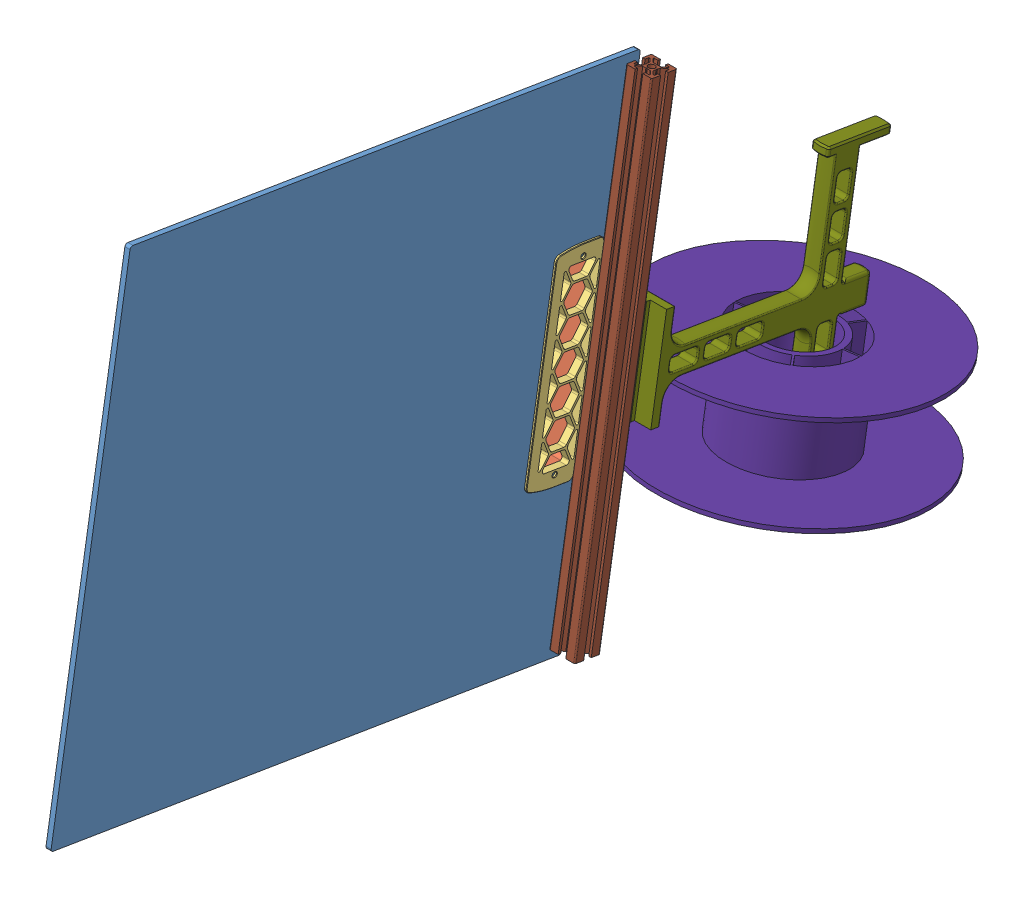
SolidWorks assembly ExhaustHousingV2, configuration Default. Lengths in mm.
Overall size (231.84 443.28 670.99).
33 component instances, 20 part files, 76 mates.
Components (placement in the parent):
- RearPanelV2-1: RearPanelV2 [Default] at (-5.1264 381.0848 346.6202) x (-1 0 0) z (0 -0.162169 -0.986763) size (4 383 403)
- FilterHousing-1: FilterHousing [Default] at (-45.6333 239.2101 122.0533) x (0 -0.986763 0.162169) z (1 0 0) size (147.2 124.67 63)
- Exhaust Grill-1: Exhaust Grill [Default] at (-84.6683 239.4745 118.2405) x (1 0 0) z (0 -0.162169 -0.986763) size (5.6 154.8 37.6)
- RoombaFilter-1: RoombaFilter [Default] at (11.8167 226.6956 67.4621) x (0 -0.986763 0.162169) z (0 -0.162169 -0.986763) size (111 58.5 10.6)
- 6020 Fan-1: 6020 Fan [Default] at (-19.2567 180.7716 130.8499) x (1 0 0) z (0 -0.162169 -0.986763) size (60 60 20.73)
  - 6020 Impeller-1: 6020 Impeller [Default] at origin size (57.63 56.86 10.88)
  - 6020 Housing-1: 6020 Housing [Default] at origin size (60 60 20.73)
- 60mm_exhaust_fan_grill-1: 60mm_exhaust_fan_grill [Default] at (-103.0418 277.1852 53.6413) x (0 -0.162169 -0.986763) z (-1 0 0) size (3.2 60 60)
- M3x30 SHCS (23)-1: M3x30 SHCS (23) [Default] at (11.2417 204.1424 113.6814) x (0.591782 0.795427 -0.130724) z (0 -0.162169 -0.986763) size (5.5 5.5 33.14)
- M3x30 SHCS (23)-2: M3x30 SHCS (23) [Default] at (11.2417 154.4342 121.8506) x (1 0 0) z (0 -0.162169 -0.986763) size (5.5 5.5 33.14)
- M3x30 SHCS (23)-3: M3x30 SHCS (23) [Default] at (-39.1333 154.4342 121.8506) x (1 0 0) z (0 -0.162169 -0.986763) size (5.5 5.5 33.14)
- M3x30 SHCS (23)-4: M3x30 SHCS (23) [Default] at (-39.1333 204.1424 113.6814) x (1 0 0) z (0 -0.162169 -0.986763) size (5.5 5.5 33.14)
- SF2-1: SF2 [Default] at (-36.5033 186.0161 -0.4675) x (0 -0.986763 0.162169) z (-0.707107 0.114671 0.697747) size (53 27 31)
- M3x8 SHCS (91)-3: M3x8 SHCS (91) [Default] at (-49.2312 178.623 40.8767) x (0.696904 -0.054007 0.715128) z (-0.707107 0.114671 0.697747) size (5.5 5.5 11.14)
- M3x8 SHCS (91)-2: M3x8 SHCS (91) [Default] at (-58.0701 152.5205 36.2091) x (-0.176014 0.927159 -0.330749) z (-0.707107 0.114671 0.697747) size (5.5 5.5 11.14)
- M3x8 SHCS (91)-1: M3x8 SHCS (91) [Default] at (-49.2312 153.9539 44.9309) x (0.040643 0.991723 -0.121796) z (-0.707107 0.114671 0.697747) size (5.5 5.5 11.14)
- HFSB5-2020-370-TPW-1: HFSB5-2020-370-TPW [Default] at (210.7912 17.5776 81.3371) x (-1 0 0) z (0 -0.986763 0.162169) size (20 20 370)
  - HFSB5-2020-370-TPW (1)-1: HFSB5-2020-370-TPW (1) [Default] at (179.4245 40.4288 32.2963) size (20 20 370)
  - 2020 Drop-in T-nut, M5-1-1: 2020 Drop-in T-nut, M5-1 [Default] at (188.0245 39.8788 -223.8496) x (0 1 0) z (0 0 -1) size (7.7 4.3 13)
  - 2020 Drop-in T-nut, M5-2-1: 2020 Drop-in T-nut, M5-2 [Default] at (188.0245 39.8788 -81.775) x (0 -1 0) z (0 0 1) size (7.7 4.3 13)
- ExhaustSpacer-1: ExhaustSpacer [Default] at (-84.6683 239.5069 118.4376) x (1 0 0) z (0 -0.162169 -0.986763) size (4 146.4 51.6)
- M5x10 BHCS-1: M5x10 BHCS [Default] at (14.6167 99.6972 27.4274) x (0 -0.535626 -0.844456) z (-1 0 0) size (9.57 9.61 13.38)
- M5x10 BHCS-2: M5x10 BHCS [Default] at (14.6167 224.424 6.9292) x (0 -0.013666 -0.999907) z (-1 0 0) size (9.57 9.61 13.38)
- SpoolHolderfor2V2-1: SpoolHolderfor2V2 [Default] at (153.0824 49.3334 -39.749) x (0 -0.162169 -0.986763) z (1 0 0) size (176.82 207.23 38.86)
- FilamentSpool200x72mm-1: FilamentSpool200x72mm [Default] at (47.0709 125.7193 -111.542) x (0.984651 -0.028305 -0.172227) z (0 -0.986763 0.162169) size (200 200 73.24)
- CharcoalBoxV2-1: CharcoalBoxV2 [Default] at (-45.6333 119.2164 123.3821) x (0 -0.162169 -0.986763) z (1 0 0) size (49.75 119.5 71)
- M3 Threaded Insert-1: M3 Threaded Insert [Default] at (-39.1333 155.0748 125.7483) x (1 0 0) z (0 0.162169 0.986763) size (5 5 3.85)
- M3 Threaded Insert-2: M3 Threaded Insert [Default] at (-39.1333 204.413 117.6399) x (1 0 0) z (0 0.162169 0.986763) size (5 5 3.85)
- M3 Threaded Insert-3: M3 Threaded Insert [Default] at (10.8667 155.0748 125.7483) x (1 0 0) z (0 0.162169 0.986763) size (5 5 3.85)
- M3 Threaded Insert-4: M3 Threaded Insert [Default] at (10.8667 204.413 117.6399) x (1 0 0) z (0 0.162169 0.986763) size (5 5 3.85)
- M3 Threaded Insert-5: M3 Threaded Insert [Default] at (13.5167 234.4299 31.4309) x (0 0 -1) z (1 0 0) size (5 5 3.85)
- M3 Threaded Insert-6: M3 Threaded Insert [Default] at (13.5167 98.0592 53.8427) x (0 -0.087212 -0.99619) z (1 0 0) size (5 5 3.85)
- SFSReplacement-1: SFSReplacement [Default] at (-18.8257 136.091 25.6522) x (0 0.986763 -0.162169) z (-0.707107 0.114671 0.697747) size (53.9 25 25)
Mates (geometry in assembly coordinates):
- Distance5: distance = 4 mm: line of 6020 Fan (1)-1/RoombaFilter-1 through (-41.1837 -52 36) axis (1 0 0); plane of FilterHousing-1 through (17.3667 111.7222 84.1699) normal (0 -0.156807 -0.987629)
- Distance6: distance = 38.5 mm anti-aligned: plane of FilterHousing-1 through (-45.6333 239.2101 122.0533) normal (0 -0.986763 0.162169); plane of 6020 Fan (1)-1/RoombaFilter-1 through (-41.1837 -19 34) normal (0 -1 0)
- Distance7: distance = 4 mm: line of 6020 Fan (1)-1/RoombaFilter-2 through (-41.1837 -52 36) axis (1 0 0); plane of FilterHousing-1 through (17.3667 111.7222 84.1699) normal (0 -0.156807 -0.987629)
- Distance8: distance = 38.5 mm anti-aligned: plane of FilterHousing-1 through (-45.6333 239.2101 122.0533) normal (0 -0.986763 0.162169); plane of 6020 Fan (1)-1/RoombaFilter-2 through (-41.1837 -19 34) normal (0 -1 0)
- Concentric19: concentric aligned: cylinder of M3x30 SHCS (23)-3 through (-39.1333 159.2993 151.4535) axis (0 -0.162169 -0.986763) radius 1.5; cylinder of 60mm_exhaust_fan_grill-1 through (-39.1333 159.4615 152.4403) axis (0 -0.162169 -0.986763) radius 1.75
- Concentric20: concentric aligned: cylinder of M3x30 SHCS (23)-4 through (-39.1333 209.0075 143.2843) axis (0 -0.162169 -0.986763) radius 1.5; cylinder of 60mm_exhaust_fan_grill-1 through (-39.1333 209.1697 144.271) axis (0 -0.162169 -0.986763) radius 1.75
- Concentric21: concentric aligned: cylinder of M3x30 SHCS (23)-2 through (11.2417 159.2993 151.4535) axis (0 -0.162169 -0.986763) radius 1.5; cylinder of 60mm_exhaust_fan_grill-1 through (11.2417 159.4615 152.4403) axis (0 -0.162169 -0.986763) radius 1.75
- Concentric22: concentric aligned: cylinder of M3x30 SHCS (23)-1 through (11.2417 209.0075 143.2843) axis (0 -0.162169 -0.986763) radius 1.5; cylinder of 60mm_exhaust_fan_grill-1 through (11.2417 209.1697 144.271) axis (0 -0.162169 -0.986763) radius 1.75
- Coincident45: coincident anti-aligned: plane of M3x30 SHCS (23)-1 through (11.2417 209.0075 143.2843) normal (0 -0.162169 -0.986763); plane of 60mm_exhaust_fan_grill-1 through (11.2417 209.0075 143.2843) normal (0 0.162169 0.986763)
- Coincident46: coincident anti-aligned: plane of M3x30 SHCS (23)-4 through (-39.1333 209.0075 143.2843) normal (0 -0.162169 -0.986763); plane of 60mm_exhaust_fan_grill-1 through (-39.1333 209.0075 143.2843) normal (0 0.162169 0.986763)
- Coincident47: coincident anti-aligned: plane of M3x30 SHCS (23)-3 through (-39.1333 159.2993 151.4535) normal (0 -0.162169 -0.986763); plane of 60mm_exhaust_fan_grill-1 through (-39.1333 159.2993 151.4535) normal (0 0.162169 0.986763)
- Coincident48: coincident anti-aligned: plane of M3x30 SHCS (23)-2 through (11.2417 159.2993 151.4535) normal (0 -0.162169 -0.986763); plane of 60mm_exhaust_fan_grill-1 through (11.2417 159.2993 151.4535) normal (0 0.162169 0.986763)
- Coincident49: coincident anti-aligned: plane of 6020 Fan (1)-1/6020 Housing (1)-1 through (-39.6333 158.8192 149.3029) normal (0 0.162169 0.986763); plane of 60mm_exhaust_fan_grill-1 through (-13.9458 183.7966 145.198) normal (0 -0.162169 -0.986763)
- Concentric23: concentric aligned: cylinder of 6020 Fan (1)-1/6020 Housing (1)-1 through (-39.1333 204.5965 116.4443) axis (0 -0.162169 -0.986763) radius 2.25; cylinder of M3x30 SHCS (23)-4 through (-39.1333 209.0075 143.2843) axis (0 -0.162169 -0.986763) radius 1.5
- Parallel8: parallel aligned: plane of FilterHousing-1 through (-45.6333 239.2101 122.0533) normal (-1 0 0); plane of 6020 Fan (1)-1/6020 Housing (1)-1 through (-44.1333 154.765 124.6338) normal (-1 0 0)
- Parallel13: parallel aligned: plane of FilterHousing-1 through (-45.6333 239.2101 122.0533) normal (-1 0 0); plane of 6020 Fan (1)-1/6020 Housing (1)-1 through (-44.1333 154.765 124.6338) normal (-1 0 0)
- Concentric31: concentric aligned: cylinder of ExhaustSpacer-1 through (17.3667 99.6972 27.4274) axis (1 0 0) radius 2.75; cylinder of M5x10 BHCS-1 through (27.3667 99.6972 27.4274) axis (1 0 0) radius 2.5
- Concentric32: concentric aligned: cylinder of ExhaustSpacer-1 through (17.3667 224.424 6.9292) axis (1 0 0) radius 2.75; cylinder of M5x10 BHCS-2 through (27.3667 224.424 6.9292) axis (1 0 0) radius 2.5
- Coincident77: coincident anti-aligned: plane of ExhaustSpacer-1 through (17.3667 239.5069 118.4376) normal (-1 0 0); plane of M5x10 BHCS-2 through (17.3667 229.1736 6.8643) normal (1 0 0)
- Coincident78: coincident anti-aligned: plane of ExhaustSpacer-1 through (17.3667 239.5069 118.4376) normal (-1 0 0); plane of M5x10 BHCS-1 through (17.3667 103.7083 24.8832) normal (1 0 0)
- Coincident83: coincident anti-aligned: plane of HFSB5-2020-370-TPW-1/HFSB5-2020-370-TPW (1)-1 through (34.3667 342.6332 -23.1893) normal (0 -0.162169 -0.986763); plane of SpoolHolderfor2V2-1 through (153.0824 59.6968 23.3097) normal (0 0.162169 0.986763)
- Coincident84: coincident anti-aligned: plane of HFSB5-2020-370-TPW-1/HFSB5-2020-370-TPW (1)-1 through (34.3667 342.9575 -21.2158) normal (-1 0 0); plane of SpoolHolderfor2V2-1 through (34.3667 198.552 6.5701) normal (1 0 0)
- Distance21: distance = 3 mm anti-aligned: plane of FilamentSpool200x72mm-1 through (47.0709 125.7193 -111.542) normal (0 0.986763 -0.162169); plane of SpoolHolderfor2V2-1 through (61.3108 127.2962 -120.4458) normal (0 -0.986763 0.162169)
- Concentric33: concentric aligned: cylinder of M3x30 SHCS (23)-3 through (-39.1333 159.2993 151.4535) axis (0 -0.162169 -0.986763) radius 1.5; cylinder of 6020 Fan (1)-1/60mm_exhaust_fan_grill-1 through (-39.6333 154.8032 133.1909) axis (0 -0.162169 -0.986763) radius 1.75
- Concentric34: concentric aligned: cylinder of M3x30 SHCS (23)-4 through (-39.1333 209.0075 143.2843) axis (0 -0.162169 -0.986763) radius 1.5; cylinder of 6020 Fan (1)-1/60mm_exhaust_fan_grill-1 through (-39.6333 204.5114 125.0216) axis (0 -0.162169 -0.986763) radius 1.75
- Concentric35: concentric aligned: cylinder of M3x30 SHCS (23)-2 through (11.2417 159.2993 151.4535) axis (0 -0.162169 -0.986763) radius 1.5; cylinder of 6020 Fan (1)-1/60mm_exhaust_fan_grill-1 through (10.7417 154.8032 133.1909) axis (0 -0.162169 -0.986763) radius 1.75
- Concentric36: concentric aligned: cylinder of M3x30 SHCS (23)-1 through (11.2417 209.0075 143.2843) axis (0 -0.162169 -0.986763) radius 1.5; cylinder of 6020 Fan (1)-1/60mm_exhaust_fan_grill-1 through (10.7417 204.5114 125.0216) axis (0 -0.162169 -0.986763) radius 1.75
- Coincident95: coincident anti-aligned: plane of M3x30 SHCS (23)-1 through (11.2417 209.0075 143.2843) normal (0 -0.162169 -0.986763); plane of 6020 Fan (1)-1/60mm_exhaust_fan_grill-1 through (10.7417 204.3492 124.0349) normal (0 0.162169 0.986763)
- Coincident96: coincident anti-aligned: plane of M3x30 SHCS (23)-4 through (-39.1333 209.0075 143.2843) normal (0 -0.162169 -0.986763); plane of 6020 Fan (1)-1/60mm_exhaust_fan_grill-1 through (-39.6333 204.3492 124.0349) normal (0 0.162169 0.986763)
- Coincident97: coincident anti-aligned: plane of M3x30 SHCS (23)-3 through (-39.1333 159.2993 151.4535) normal (0 -0.162169 -0.986763); plane of 6020 Fan (1)-1/60mm_exhaust_fan_grill-1 through (-39.6333 154.641 132.2041) normal (0 0.162169 0.986763)
- Coincident98: coincident anti-aligned: plane of M3x30 SHCS (23)-2 through (11.2417 159.2993 151.4535) normal (0 -0.162169 -0.986763); plane of 6020 Fan (1)-1/60mm_exhaust_fan_grill-1 through (10.7417 154.641 132.2041) normal (0 0.162169 0.986763)
- Coincident103: coincident anti-aligned: plane of RoombaFilter-1 through (11.8167 226.6956 67.4621) normal (0 0.162169 0.986763); plane of CarcoalBoxV2-1 through (-45.6333 113.0945 86.1318) normal (0 -0.162169 -0.986763)
- Coincident104: coincident aligned: line of RoombaFilter-1 through (10.8173 117.1649 85.4629) axis (-1 0 0); line of CarcoalBoxV2-1 through (11.9167 117.1649 85.4629) axis (-1 0 0)
- Coincident105: coincident aligned: line of RoombaFilter-1 through (-43.1833 118.1511 85.3008) axis (0 0.986763 -0.162169); line of CarcoalBoxV2-1 through (-43.1833 117.1649 85.4629) axis (0 0.986763 -0.162169)
- Distance26: distance = 0.1 mm anti-aligned: plane of FilterHousing-1 through (-42.7333 119.6043 126.3586) normal (0 0.986763 -0.162169); plane of CarcoalBoxV2-1 through (14.3667 119.2164 123.3821) normal (0 -0.986763 0.162169)
- Coincident107: coincident anti-aligned: plane of FilterHousing-1 through (-36.5033 186.5095 -0.5486) normal (-0.707107 0.114671 0.697747); plane of SF2-1 through (-36.5033 186.0161 -0.4675) normal (0.707107 -0.114671 -0.697747)
- Coincident108: coincident aligned: plane of FilterHousing-1 through (-105.831 229.4478 62.6524) normal (-0.707107 -0.114671 -0.697747); plane of SF2-1 through (-54.181 188.8828 16.9762) normal (-0.707107 -0.114671 -0.697747)
- Distance27: distance = 47 mm aligned: plane of SF2-1 through (-54.181 188.8828 16.9762) normal (0 0.986763 -0.162169); plane of FilterHousing-1 through (-45.6333 236.0634 14.2384) normal (0 0.986763 -0.162169)
- Concentric37: concentric anti-aligned: cylinder of FilterHousing-1 through (-39.1333 153.7531 117.7062) axis (0 0.162169 0.986763) radius 2.1; cylinder of M3 Threaded Insert-1 through (-39.1333 155.0748 125.7483) axis (0 -0.162169 -0.986763) radius 1.45
- Concentric38: concentric anti-aligned: cylinder of FilterHousing-1 through (10.8667 153.7531 117.7062) axis (0 0.162169 0.986763) radius 2.1; cylinder of M3 Threaded Insert-3 through (10.8667 155.0748 125.7483) axis (0 -0.162169 -0.986763) radius 1.45
- Concentric39: concentric anti-aligned: cylinder of FilterHousing-1 through (-39.1333 203.0913 109.5978) axis (0 0.162169 0.986763) radius 2.1; cylinder of M3 Threaded Insert-2 through (-39.1333 204.413 117.6399) axis (0 -0.162169 -0.986763) radius 1.45
- Concentric40: concentric anti-aligned: cylinder of FilterHousing-1 through (10.8667 203.0913 109.5978) axis (0 0.162169 0.986763) radius 2.1; cylinder of M3 Threaded Insert-4 through (10.8667 204.413 117.6399) axis (0 -0.162169 -0.986763) radius 1.45
- Coincident109: coincident aligned: plane of FilterHousing-1 through (-45.6333 238.213 115.9867) normal (0 0.162169 0.986763); plane of M3 Threaded Insert-1 through (-39.1333 155.6992 129.5474) normal (0 0.162169 0.986763)
- Coincident110: coincident aligned: plane of FilterHousing-1 through (-45.6333 238.213 115.9867) normal (0 0.162169 0.986763); plane of M3 Threaded Insert-3 through (10.8667 155.6992 129.5474) normal (0 0.162169 0.986763)
- Coincident111: coincident aligned: plane of FilterHousing-1 through (-45.6333 238.213 115.9867) normal (0 0.162169 0.986763); plane of M3 Threaded Insert-4 through (10.8667 205.0373 121.4389) normal (0 0.162169 0.986763)
- Coincident112: coincident aligned: plane of FilterHousing-1 through (-45.6333 238.213 115.9867) normal (0 0.162169 0.986763); plane of M3 Threaded Insert-2 through (-39.1333 205.0373 121.4389) normal (0 0.162169 0.986763)
- Concentric41: concentric anti-aligned: cylinder of FilterHousing-1 through (11.3667 234.4299 31.4309) axis (1 0 0) radius 2.1; cylinder of M3 Threaded Insert-5 through (13.5167 234.4299 31.4309) axis (-1 0 0) radius 1.45
- Coincident113: coincident aligned: plane of FilterHousing-1 through (17.3667 239.2101 122.0533) normal (1 0 0); plane of M3 Threaded Insert-5 through (17.3667 234.4299 31.4309) normal (1 0 0)
- Concentric42: concentric anti-aligned: cylinder of FilterHousing-1 through (11.3667 98.0592 53.8427) axis (1 0 0) radius 2.1; cylinder of M3 Threaded Insert-6 through (13.5167 98.0592 53.8427) axis (-1 0 0) radius 1.45
- Coincident114: coincident aligned: plane of FilterHousing-1 through (17.3667 239.2101 122.0533) normal (1 0 0); plane of M3 Threaded Insert-6 through (17.3667 98.0592 53.8427) normal (1 0 0)
- Coincident115: coincident anti-aligned: plane of FilterHousing-1 through (17.3667 239.2101 122.0533) normal (1 0 0); plane of Exhaust Grill-1 through (17.3667 166.2445 42.6368) normal (-1 0 0)
- Concentric43: concentric aligned: cylinder of Exhaust Grill-1 through (22.9667 234.4299 31.4309) axis (-1 0 0) radius 1.7; cylinder of M3 Threaded Insert-5 through (13.5167 234.4299 31.4309) axis (-1 0 0) radius 1.45
- Concentric44: concentric aligned: cylinder of Exhaust Grill-1 through (22.9667 98.0592 53.8427) axis (-1 0 0) radius 1.7; cylinder of M3 Threaded Insert-6 through (13.5167 98.0592 53.8427) axis (-1 0 0) radius 1.45
- Coincident116: coincident anti-aligned: plane of FilterHousing-1 through (17.3667 239.2101 122.0533) normal (1 0 0); plane of ExhaustSpacer-1 through (17.3667 239.5069 118.4376) normal (-1 0 0)
- Coincident117: coincident anti-aligned: plane of Exhaust Grill-1 through (17.7667 100.3321 37.4572) normal (0 -0.162169 -0.986763); plane of ExhaustSpacer-1 through (21.3667 96.9771 38.0086) normal (0 0.162169 0.986763)
- Concentric45: concentric anti-aligned: cylinder of Exhaust Grill-1 through (22.9667 98.0592 53.8427) axis (-1 0 0) radius 1.7; cylinder of ExhaustSpacer-1 through (17.3667 98.0592 53.8427) axis (1 0 0) radius 1.7
- Coincident118: coincident anti-aligned: plane of FilterHousing-1 through (-45.6333 238.213 115.9867) normal (0 0.162169 0.986763); plane of 6020 Fan (1)-1/6020 Housing (1)-1 through (-39.6333 155.5758 129.5676) normal (0 -0.162169 -0.986763)
- Coincident119: coincident anti-aligned: plane of FilterHousing-1 through (-45.6333 236.267 104.1455) normal (0 -0.162169 -0.986763); plane of CarcoalBoxV2-1 through (14.3667 119.2164 123.3821) normal (0 0.162169 0.986763)
- Concentric46: concentric aligned: cylinder of M3x30 SHCS (23)-3 through (-39.1333 159.2993 151.4535) axis (0 -0.162169 -0.986763) radius 1.5; cylinder of M3 Threaded Insert-1 through (-39.1333 155.0748 125.7483) axis (0 -0.162169 -0.986763) radius 1.45
- Parallel14: parallel aligned: plane of 6020 Fan (1)-1/6020 Housing (1)-1 through (-44.1333 154.765 124.6338) normal (-1 0 0); plane of 60mm_exhaust_fan_grill-1 through (-43.9458 209.1537 142.2468) normal (-1 0 0)
- Concentric49: concentric aligned: cylinder of FilterHousing-1 through (4.5132 169.9073 -12.1563) axis (-0.707107 0.114671 0.697747) radius 1.6; cylinder of M3x8 SHCS (91)-3 through (-20.947 174.0361 12.9668) axis (-0.707107 0.114671 0.697747) radius 1.5
- Concentric50: concentric aligned: cylinder of FilterHousing-1 through (-4.3257 143.8048 -16.8239) axis (-0.707107 0.114671 0.697747) radius 1.6; cylinder of M3x8 SHCS (91)-2 through (-29.7858 147.9337 8.2992) axis (-0.707107 0.114671 0.697747) radius 1.5
- Concentric51: concentric aligned: cylinder of FilterHousing-1 through (4.5132 145.2382 -8.1021) axis (-0.707107 0.114671 0.697747) radius 1.6; cylinder of M3x8 SHCS (91)-1 through (-20.947 149.367 17.021) axis (-0.707107 0.114671 0.697747) radius 1.5
- Coincident120: coincident anti-aligned: plane of FilterHousing-1 through (-34.382 133.3736 6.0342) normal (0.707107 -0.114671 -0.697747); plane of M3x8 SHCS (91)-2 through (-29.7858 147.9337 8.2992) normal (-0.707107 0.114671 0.697747)
- Coincident121: coincident anti-aligned: plane of FilterHousing-1 through (-34.382 133.3736 6.0342) normal (0.707107 -0.114671 -0.697747); plane of M3x8 SHCS (91)-1 through (-20.947 149.367 17.021) normal (-0.707107 0.114671 0.697747)
- Coincident122: coincident anti-aligned: plane of FilterHousing-1 through (-34.382 133.3736 6.0342) normal (0.707107 -0.114671 -0.697747); plane of M3x8 SHCS (91)-3 through (-20.947 174.0361 12.9668) normal (-0.707107 0.114671 0.697747)
- Coincident123: coincident anti-aligned: plane of RearPanelV2-1 through (21.3667 234.47 6.393) normal (0 -0.986763 0.162169); plane of ExhaustSpacer-1 through (21.3667 232.6699 -4.5601) normal (0 0.986763 -0.162169)
- Coincident124: coincident anti-aligned: plane of RearPanelV2-1 through (21.3667 237.5842 46.9245) normal (0 -0.162169 -0.986763); plane of Exhaust Grill-1 through (17.7667 105.4566 68.6389) normal (0 0.162169 0.986763)
- Coincident125: coincident anti-aligned: plane of RearPanelV2-1 through (21.3667 39.6342 442.7656) normal (1 0 0); plane of Exhaust Grill-1 through (21.3667 166.2445 42.6368) normal (-1 0 0)
- Coincident126: coincident anti-aligned: plane of RearPanelV2-1 through (21.3667 39.6342 442.7656) normal (1 0 0); plane of HFSB5-2020-370-TPW-1/HFSB5-2020-370-TPW (1)-1 through (21.3667 345.7144 -4.4408) normal (-1 0 0)
- Concentric52: concentric aligned: cylinder of HFSB5-2020-370-TPW-1/2020 Drop-in T-nut, M5 (21)-1 through (21.211 99.6972 27.4274) axis (1 0 0) radius 2.1; cylinder of ExhaustSpacer-1 through (17.3667 99.6972 27.4274) axis (1 0 0) radius 2.75
- Parallel15: parallel anti-aligned: plane of RearPanelV2-1 through (21.3667 348.5875 -14.3884) normal (0 -0.162169 -0.986763); plane of HFSB5-2020-370-TPW-1/HFSB5-2020-370-TPW (1)-1 through (28.3667 345.8765 -3.454) normal (0 0.162169 0.986763)
- Distance30: distance = 147 mm aligned: plane of SpoolHolderfor2V2-1 through (42.0827 196.1221 -8.2155) normal (0 0.986763 -0.162169); plane of HFSB5-2020-370-TPW-1/HFSB5-2020-370-TPW (1)-1 through (40.3667 345.7144 -4.4408) normal (0 0.986763 -0.162169)
- Coincident130: coincident anti-aligned: plane of FilterHousing-1 through (-36.5033 186.5095 -0.5486) normal (-0.707107 0.114671 0.697747); plane of SFSReplacement-1 through (-18.8257 136.091 25.6522) normal (0.707107 -0.114671 -0.697747)
- Coincident131: coincident anti-aligned: plane of FilterHousing-1 through (-42.8673 134.2563 14.4883) normal (0 0.986763 -0.162169); plane of SFSReplacement-1 through (-20.2399 136.3204 27.0477) normal (0 -0.986763 0.162169)
- Coincident132: coincident anti-aligned: plane of FilterHousing-1 through (-88.1533 232.3146 80.0961) normal (-0.707107 -0.114671 -0.697747); plane of SFSReplacement-1 through (-20.2399 136.3204 27.0477) normal (0.707107 0.114671 0.697747)
